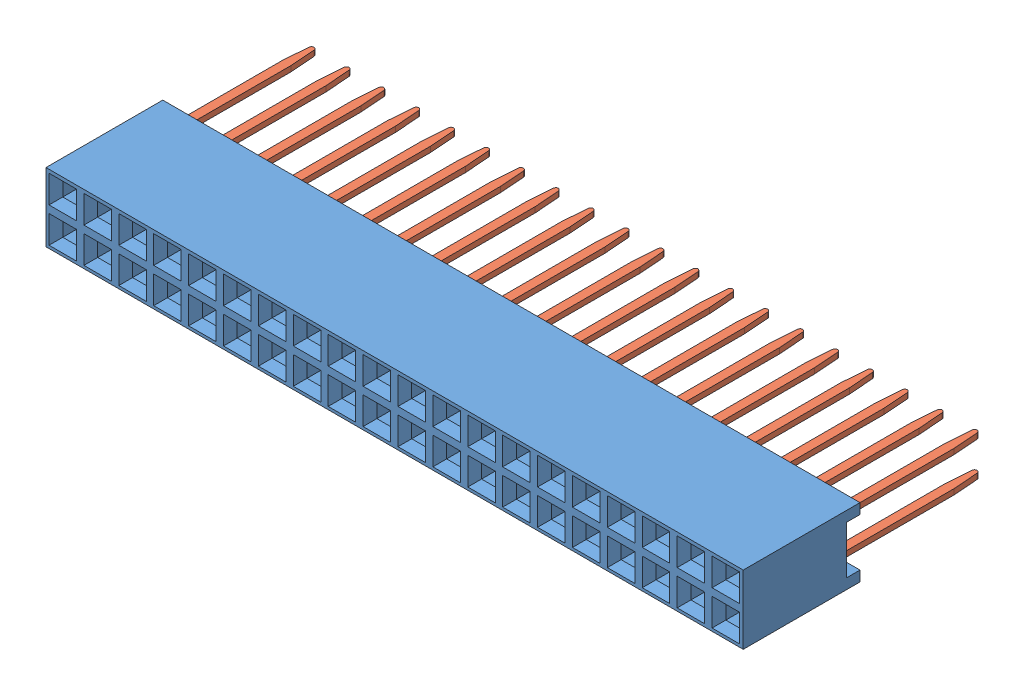
SolidWorks assembly 960240-6202-AR, configuration Default. Lengths in mm.
Overall size (50.75 5 18.29).
41 component instances, 2 part files, 0 mates.
Components (placement in the parent):
- 960240-6202-AR Body_1-1: 960240-6202-AR Body_1 [Default] at (1.481 -2.997 1.2546) size (50.75 5 8.5)
- 960240-6202-AR Pin_1-1: 960240-6202-AR Pin_1 [Default] at (0.211 0.853 -17.0352) x (1 0 0) z (0 -1 0) size (2 16.29 0.4)
- 960240-6202-AR Pin_1-2: 960240-6202-AR Pin_1 [Default] at (0.211 -1.687 -17.0352) x (1 0 0) z (0 -1 0) size (2 16.29 0.4)
- 960240-6202-AR Pin_1-3: 960240-6202-AR Pin_1 [Default] at (-2.329 0.853 -17.0352) x (1 0 0) z (0 -1 0) size (2 16.29 0.4)
- 960240-6202-AR Pin_1-4: 960240-6202-AR Pin_1 [Default] at (-2.329 -1.687 -17.0352) x (1 0 0) z (0 -1 0) size (2 16.29 0.4)
- 960240-6202-AR Pin_1-5: 960240-6202-AR Pin_1 [Default] at (-4.869 0.853 -17.0352) x (1 0 0) z (0 -1 0) size (2 16.29 0.4)
- 960240-6202-AR Pin_1-6: 960240-6202-AR Pin_1 [Default] at (-4.869 -1.687 -17.0352) x (1 0 0) z (0 -1 0) size (2 16.29 0.4)
- 960240-6202-AR Pin_1-7: 960240-6202-AR Pin_1 [Default] at (-7.409 0.853 -17.0352) x (1 0 0) z (0 -1 0) size (2 16.29 0.4)
- 960240-6202-AR Pin_1-8: 960240-6202-AR Pin_1 [Default] at (-7.409 -1.687 -17.0352) x (1 0 0) z (0 -1 0) size (2 16.29 0.4)
- 960240-6202-AR Pin_1-9: 960240-6202-AR Pin_1 [Default] at (-9.949 0.853 -17.0352) x (1 0 0) z (0 -1 0) size (2 16.29 0.4)
- 960240-6202-AR Pin_1-10: 960240-6202-AR Pin_1 [Default] at (-9.949 -1.687 -17.0352) x (1 0 0) z (0 -1 0) size (2 16.29 0.4)
- 960240-6202-AR Pin_1-11: 960240-6202-AR Pin_1 [Default] at (-12.489 0.853 -17.0352) x (1 0 0) z (0 -1 0) size (2 16.29 0.4)
- 960240-6202-AR Pin_1-12: 960240-6202-AR Pin_1 [Default] at (-12.489 -1.687 -17.0352) x (1 0 0) z (0 -1 0) size (2 16.29 0.4)
- 960240-6202-AR Pin_1-13: 960240-6202-AR Pin_1 [Default] at (-15.029 0.853 -17.0352) x (1 0 0) z (0 -1 0) size (2 16.29 0.4)
- 960240-6202-AR Pin_1-14: 960240-6202-AR Pin_1 [Default] at (-15.029 -1.687 -17.0352) x (1 0 0) z (0 -1 0) size (2 16.29 0.4)
- 960240-6202-AR Pin_1-15: 960240-6202-AR Pin_1 [Default] at (-17.569 0.853 -17.0352) x (1 0 0) z (0 -1 0) size (2 16.29 0.4)
- 960240-6202-AR Pin_1-16: 960240-6202-AR Pin_1 [Default] at (-17.569 -1.687 -17.0352) x (1 0 0) z (0 -1 0) size (2 16.29 0.4)
- 960240-6202-AR Pin_1-17: 960240-6202-AR Pin_1 [Default] at (-20.109 0.853 -17.0352) x (1 0 0) z (0 -1 0) size (2 16.29 0.4)
- 960240-6202-AR Pin_1-18: 960240-6202-AR Pin_1 [Default] at (-20.109 -1.687 -17.0352) x (1 0 0) z (0 -1 0) size (2 16.29 0.4)
- 960240-6202-AR Pin_1-19: 960240-6202-AR Pin_1 [Default] at (-22.649 0.853 -17.0352) x (1 0 0) z (0 -1 0) size (2 16.29 0.4)
- 960240-6202-AR Pin_1-20: 960240-6202-AR Pin_1 [Default] at (-22.649 -1.687 -17.0352) x (1 0 0) z (0 -1 0) size (2 16.29 0.4)
- 960240-6202-AR Pin_1-21: 960240-6202-AR Pin_1 [Default] at (-25.189 0.853 -17.0352) x (1 0 0) z (0 -1 0) size (2 16.29 0.4)
- 960240-6202-AR Pin_1-22: 960240-6202-AR Pin_1 [Default] at (-25.189 -1.687 -17.0352) x (1 0 0) z (0 -1 0) size (2 16.29 0.4)
- 960240-6202-AR Pin_1-23: 960240-6202-AR Pin_1 [Default] at (-27.729 0.853 -17.0352) x (1 0 0) z (0 -1 0) size (2 16.29 0.4)
- 960240-6202-AR Pin_1-24: 960240-6202-AR Pin_1 [Default] at (-27.729 -1.687 -17.0352) x (1 0 0) z (0 -1 0) size (2 16.29 0.4)
- 960240-6202-AR Pin_1-25: 960240-6202-AR Pin_1 [Default] at (-30.269 0.853 -17.0352) x (1 0 0) z (0 -1 0) size (2 16.29 0.4)
- 960240-6202-AR Pin_1-26: 960240-6202-AR Pin_1 [Default] at (-30.269 -1.687 -17.0352) x (1 0 0) z (0 -1 0) size (2 16.29 0.4)
- 960240-6202-AR Pin_1-27: 960240-6202-AR Pin_1 [Default] at (-32.809 0.853 -17.0352) x (1 0 0) z (0 -1 0) size (2 16.29 0.4)
- 960240-6202-AR Pin_1-28: 960240-6202-AR Pin_1 [Default] at (-32.809 -1.687 -17.0352) x (1 0 0) z (0 -1 0) size (2 16.29 0.4)
- 960240-6202-AR Pin_1-29: 960240-6202-AR Pin_1 [Default] at (-35.349 0.853 -17.0352) x (1 0 0) z (0 -1 0) size (2 16.29 0.4)
- 960240-6202-AR Pin_1-30: 960240-6202-AR Pin_1 [Default] at (-35.349 -1.687 -17.0352) x (1 0 0) z (0 -1 0) size (2 16.29 0.4)
- 960240-6202-AR Pin_1-31: 960240-6202-AR Pin_1 [Default] at (-37.889 0.853 -17.0352) x (1 0 0) z (0 -1 0) size (2 16.29 0.4)
- 960240-6202-AR Pin_1-32: 960240-6202-AR Pin_1 [Default] at (-37.889 -1.687 -17.0352) x (1 0 0) z (0 -1 0) size (2 16.29 0.4)
- 960240-6202-AR Pin_1-33: 960240-6202-AR Pin_1 [Default] at (-40.429 0.853 -17.0352) x (1 0 0) z (0 -1 0) size (2 16.29 0.4)
- 960240-6202-AR Pin_1-34: 960240-6202-AR Pin_1 [Default] at (-40.429 -1.687 -17.0352) x (1 0 0) z (0 -1 0) size (2 16.29 0.4)
- 960240-6202-AR Pin_1-35: 960240-6202-AR Pin_1 [Default] at (-42.969 0.853 -17.0352) x (1 0 0) z (0 -1 0) size (2 16.29 0.4)
- 960240-6202-AR Pin_1-36: 960240-6202-AR Pin_1 [Default] at (-42.969 -1.687 -17.0352) x (1 0 0) z (0 -1 0) size (2 16.29 0.4)
- 960240-6202-AR Pin_1-37: 960240-6202-AR Pin_1 [Default] at (-45.509 0.853 -17.0352) x (1 0 0) z (0 -1 0) size (2 16.29 0.4)
- 960240-6202-AR Pin_1-38: 960240-6202-AR Pin_1 [Default] at (-45.509 -1.687 -17.0352) x (1 0 0) z (0 -1 0) size (2 16.29 0.4)
- 960240-6202-AR Pin_1-39: 960240-6202-AR Pin_1 [Default] at (-48.049 0.853 -17.0352) x (1 0 0) z (0 -1 0) size (2 16.29 0.4)
- 960240-6202-AR Pin_1-40: 960240-6202-AR Pin_1 [Default] at (-48.049 -1.687 -17.0352) x (1 0 0) z (0 -1 0) size (2 16.29 0.4)
